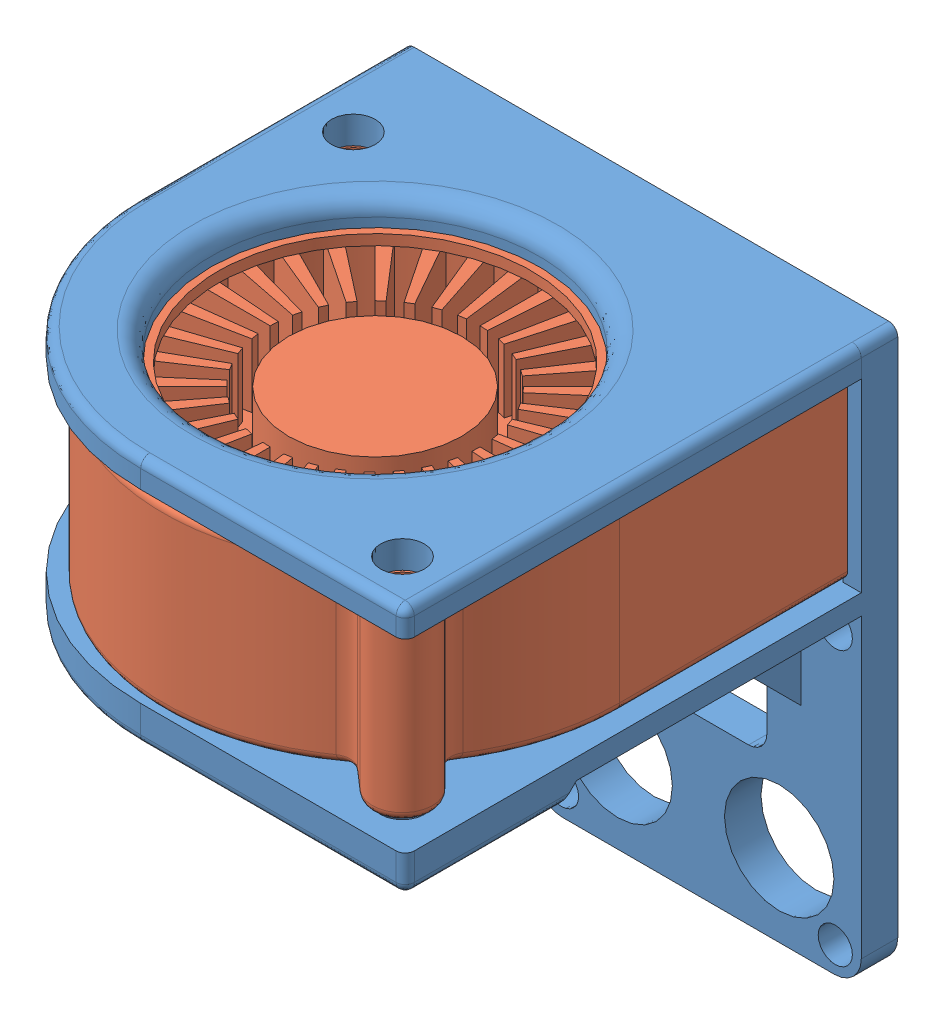
SolidWorks assembly hot-end-cooling-assembly, configuration Default. Lengths in mm.
Overall size (54.05 61.05 54).
2 component instances, 2 part files, 3 mates.
Components (placement in the parent):
- fanduct-1: fanduct [Default] at (-7.4983 1.3043 -21.0628) size (54.05 61.05 54)
- radialFan-50mm-1: radialFan-50mm [Default] at (-37.1059 25.4361 -0.1939) x (-1 0 0) z (0 1 0) size (50.1 50 20.19)
Mates (geometry in assembly coordinates):
- Coincident1: coincident anti-aligned: plane of fanduct-1 through (-38.8059 45.4361 -17.0628) normal (0 -1 0); plane of radialFan-50mm-1 through (-37.1059 45.4361 7.9372) normal (0 1 0)
- Coincident2: coincident anti-aligned: plane of fanduct-1 through (-13.5459 -9.6239 -17.0628) normal (0 0 1); plane of radialFan-50mm-1 through (-12.1059 26.5861 -17.0628) normal (0 0 -1)
- Distance1: distance = 0.5 mm anti-aligned: plane of radialFan-50mm-1 through (-12.1059 26.5861 7.9372) normal (1 0 0); plane of fanduct-1 through (-12.6059 45.4361 -17.0628) normal (-1 0 0)
